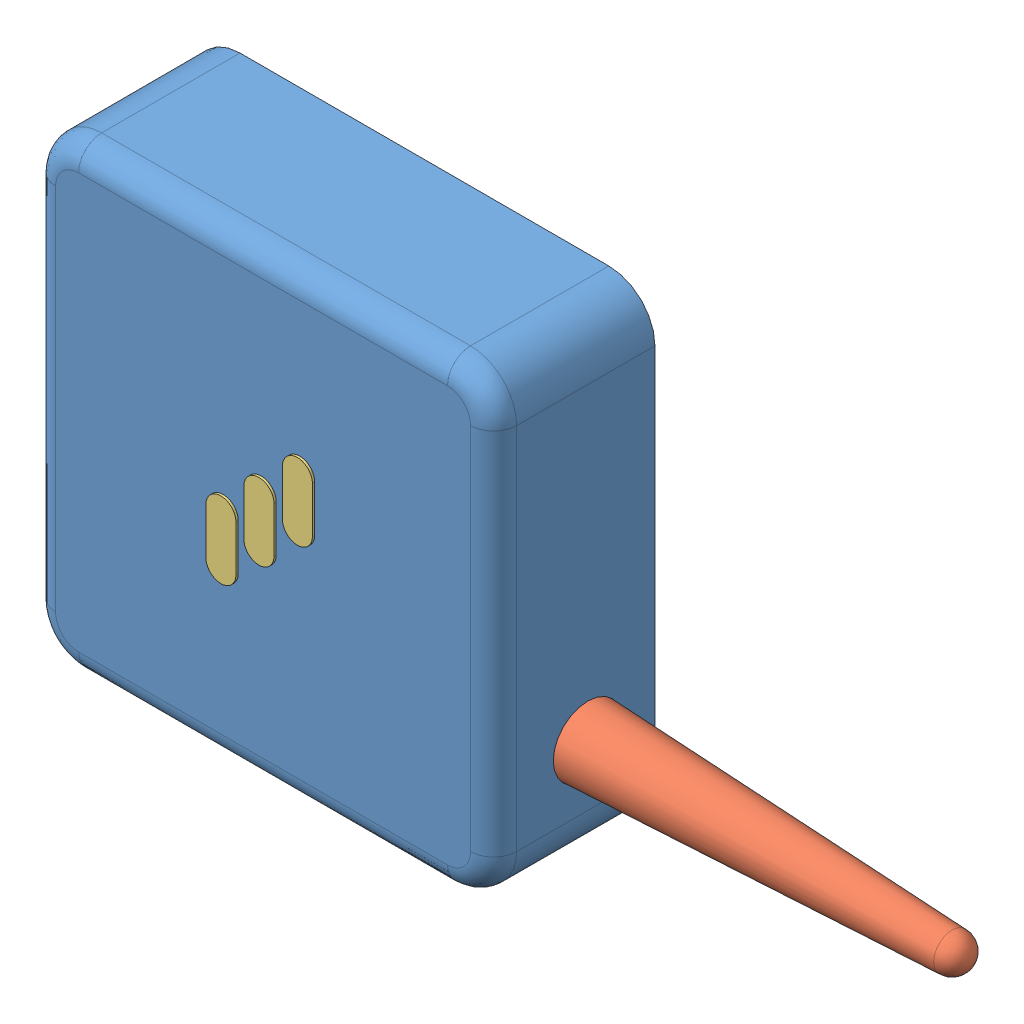
SolidWorks assembly Assem1, configuration Default. Lengths in mm.
Overall size (183 100 35.5).
5 component instances, 3 part files, 4 mates.
Components (placement in the parent):
- Hub-1: Hub [Default] at (-6.0259 33.7586 -17.1621) size (100 100 35)
- antenna-1: antenna [Default] at (141.2052 7.1659 -2.6117) size (84 15 15)
- HubCover-1: HubCover [Default] at (11.9627 -14.1259 17.8379) size (6.51 16.48 0.5)
- HubCover-2: HubCover [Default] at (28.5547 1.3846 17.8379) size (6.51 16.48 0.5)
- HubCover-4: HubCover [Default] at (20.2087 -6.5282 17.8379) size (6.51 16.48 0.5)
Mates (geometry in assembly coordinates):
- Coincident10: coincident aligned: circle of Hub-1; circle of HubCover-2
- Coincident11: coincident aligned: circle of Hub-1; circle of HubCover-1
- Coincident12: coincident anti-aligned: circle of Hub-1; circle of antenna-1
- Coincident13: coincident aligned: circle of Hub-1; circle of HubCover-4
